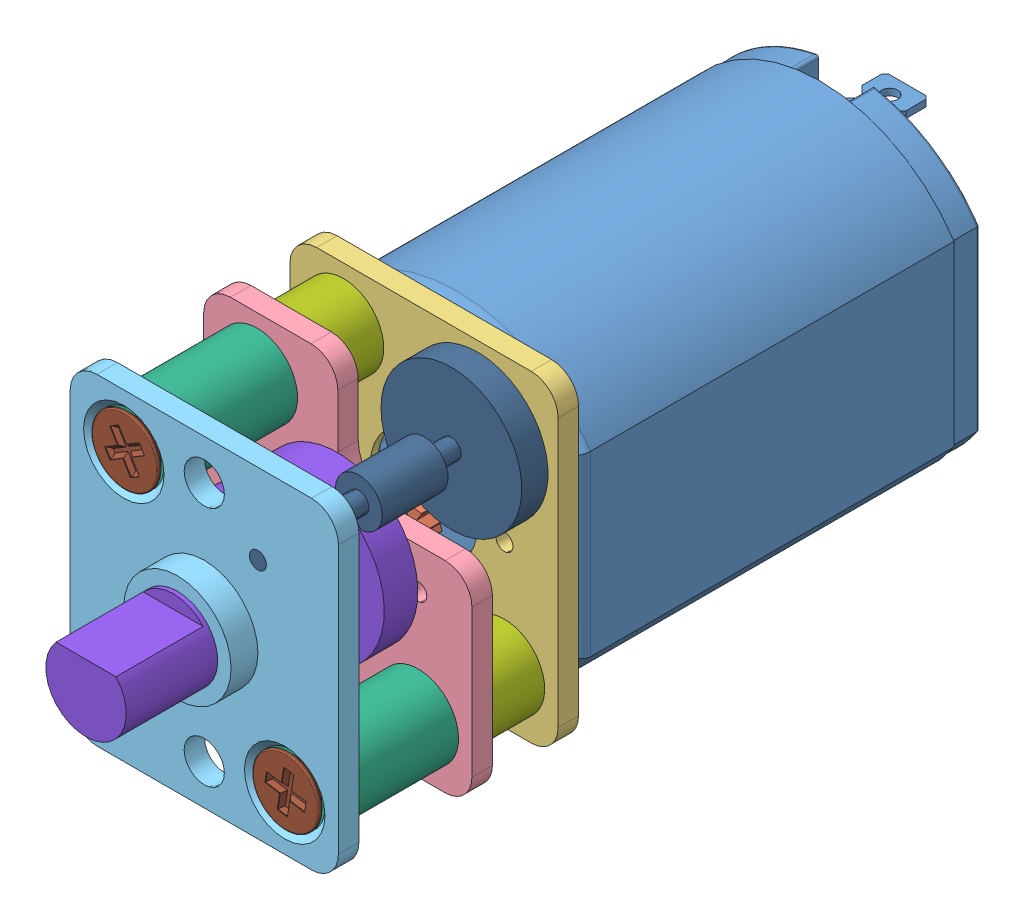
SolidWorks assembly GM12_Assem, configuration Default. Lengths in mm.
Overall size (10.07 14.62 30.61).
14 component instances, 11 part files, 0 mates.
Components (placement in the parent):
- RM4-1: RM4 [Default] at origin size (10.07 14.62 20.05)
- shaft_gear-1: shaft_gear [Default] at (0 0 14.95) x (0.993078 -0.117454 0) z (0 0 1) size (2.14 2.14 0.89)
- plate_bottom-1: plate_bottom [Default] at (5 -6 14.762) x (0 1 0) z (0 0 -1) size (12 10 0.76)
- plate_middle-1: plate_middle [Default] at (5 -6 17.974) x (0 1 0) z (0 0 -1) size (12 10 0.76)
- plate_top-1: plate_top [Default] at (5 -6 22.9524) x (0 1 0) z (0 0 -1) size (12 10 1.76)
- stndoff_lng-1: stndoff_lng [Default] at (-3 4 17.974) size (3 3 4.98)
- stndoff_lng-2: stndoff_lng [Default] at (3 -4 17.974) x (-0.917549 0.397622 0) z (0 0 1) size (3 3 4.98)
- stndoff_shrt-1: stndoff_shrt [Default] at (3 -4 14.762) size (3 3 3.21)
- stndoff_shrt-2: stndoff_shrt [Default] at (-3 4 14.762) size (3 3 3.21)
- Shaft-1: Shaft [Default] at (0 0 20.4904) size (6 6 10.13)
- gear_2-1: gear_2 [Default] at (-2 -3 19.2654) size (5.25 5.25 5.5)
- gear_1-1: gear_1 [Default] at (2 3 14.7404) size (5.25 5.25 8.97)
- screw_sm_taper-1: screw_sm_taper [Default] at (3 -4 22.5714) x (0.986821 -0.161819 0) z (0 0 1) size (2.5 2.5 0.35)
- screw_sm_taper-2: screw_sm_taper [Default] at (-3 4 22.5714) x (0.856518 0.516117 0) z (0 0 1) size (2.5 2.5 0.35)
